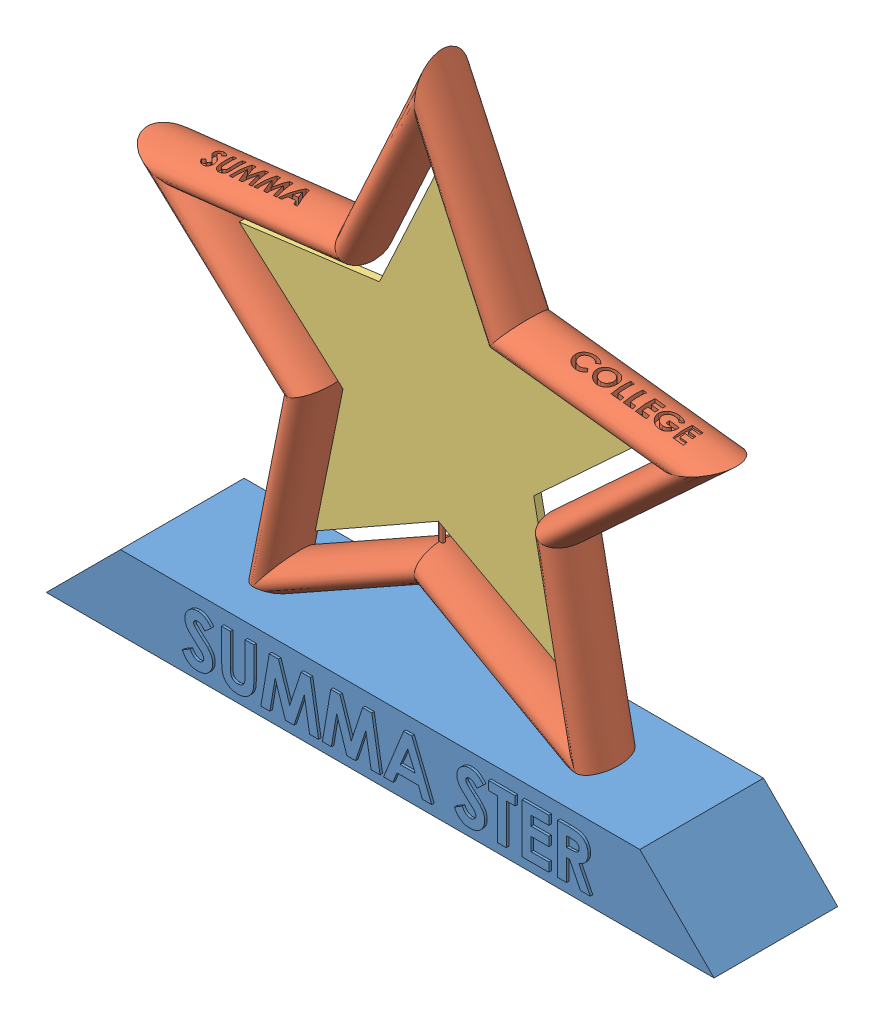
SolidWorks assembly ster troffee x1.5 in kleur, configuration Default. Lengths in mm.
Overall size (270 246.44 51).
3 component instances, 3 part files, 8 mates.
Components (placement in the parent):
- onderstuk x1.5-1: onderstuk x1.5 [Default] at origin size (270 30 51)
- bovenstuk ster x2-1: bovenstuk ster x2 [Default] at (0 30 0) size (240.62 217.61 24.94)
- ster draaideel x2-1: ster draaideel x2 [Default] at (0 53.1525 0) x (0.999888 0 -0.014933) z (0.014933 0 0.999888) size (158.7 148.42 3)
Mates (geometry in assembly coordinates):
- Coincident2: coincident: plane of onderstuk x1.5-1 through (0 0 0) normal (1 0 0); plane of assembly through (0 0 0) normal (1 0 0)
- Coincident3: coincident: plane of bovenstuk ster x2-1 through (0 30 0) normal (1 0 0); plane of assembly through (0 0 0) normal (1 0 0)
- Coincident4: coincident: plane of onderstuk x1.5-1 through (-135 30 25) normal (0 1 0); plane of bovenstuk ster x2-1 through (0 30 0) normal (0 -1 0)
- Coincident5: coincident: plane of bovenstuk ster x2-1 through (0 30 0) normal (0 0 1); plane of assembly through (0 0 0) normal (0 0 1)
- Coincident6: coincident: plane of onderstuk x1.5-1 through (0 0 0) normal (0 0 1); plane of assembly through (0 0 0) normal (0 0 1)
- Concentric1: concentric: cylinder of bovenstuk ster x2-1 through (0 69.4459 0) axis (0 1 0) radius 1; cylinder of ster draaideel x2-1 through (0 270.1525 0) axis (0 -1 0) radius 1
- Coincident9: coincident: plane of onderstuk x1.5-1 through (0 0 0) normal (0 1 0); plane of assembly through (0 0 0) normal (0 1 0)
- Distance1: distance = 7.3 mm: point of ster draaideel x2-1; point of bovenstuk ster x2-1
